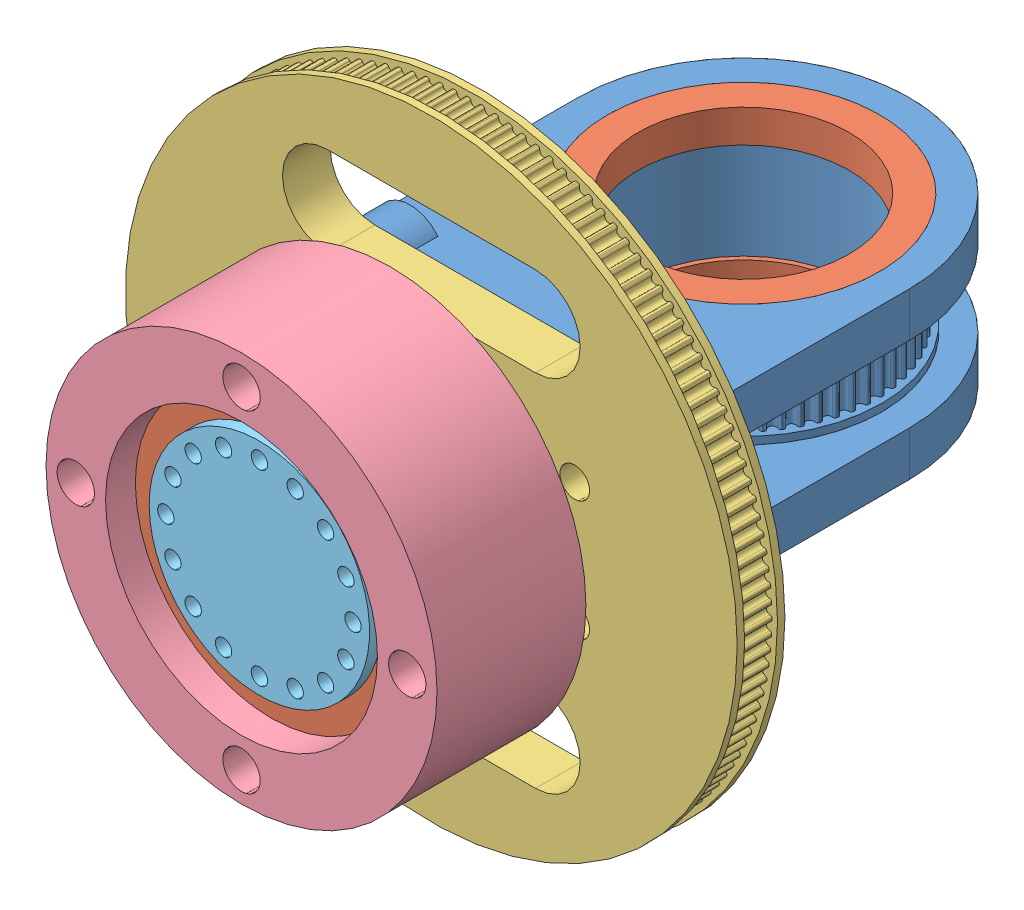
SolidWorks assembly Base, configuration Default. Lengths in mm.
Overall size (97.08 97.08 147.72).
8 component instances, 5 part files, 9 mates.
Components (placement in the parent):
- Base Joint-1: Base Joint [Default] at origin size (76.41 40.94 91.78)
- Bearing 45_58_7mm-1: Bearing 45_58_7mm [Default] at (0 14.1125 0) x (-0.796354 0 0.604831) z (0 1 0) size (58 58 7)
- Bearing 45_58_7mm-2: Bearing 45_58_7mm [Default] at (0 -14.1125 0) x (-0.796354 0 0.604831) z (0 1 0) size (58 58 7)
- Base Pulley-1: Base Pulley [Default] at (0 0 61.5165) x (0 1 0) z (1 0 0) size (97.08 44.31 97.08)
- Bearing 45_58_7mm-3: Bearing 45_58_7mm [Default] at (0 0 78.8352) x (0.359426 0.933173 0) z (0 0 -1) size (58 58 7)
- Bearing 45_58_7mm-4: Bearing 45_58_7mm [Default] at (0 0 97.2352) x (-0.999991 0.004136 0) z (0 0 -1) size (58 58 7)
- Part2^Base-1: Part2^Base [Default] at origin size (83.4 83.4 31.75) (virtual)
- Part5^Base-1: Part5^Base [Default] at origin size (47 47 2.54) (virtual)
Mates (geometry in assembly coordinates):
- Parallel1: parallel anti-aligned: plane of Bearing-1 through (0 10.6125 0) normal (0 -1 0)
- Coincident5: coincident anti-aligned: plane of Base Joint-1 through (0 10.6125 0) normal (0 1 0); plane of Bearing-1 through (0 10.6125 0) normal (0 -1 0)
- Coincident6: coincident aligned: line of Base Pulley-1 through (0 0 64.8165) axis (0 0 -1)
- Coincident7: coincident aligned: plane of Base Pulley-1 through (0 0 61.5165) normal (0 1 0)
- Coincident8: coincident anti-aligned: plane of Base Joint-1 through (-35.35 17.6125 56.429) normal (0 0 1); plane of Base Pulley-1 through (0 0 56.429) normal (0 0 -1)
- Concentric3: concentric anti-aligned: cylinder of Base Pulley-1 through (0 0 100.7352) axis (0 0 -1) radius 22.5; cylinder of Bearing 45_58_7mm-3 through (0 0 75.3352) axis (0 0 1) radius 22.5
- Coincident37: coincident anti-aligned: plane of Base Pulley-1 through (0 0 75.3352) normal (0 0 1); plane of Bearing 45_58_7mm-3 through (0 0 75.3352) normal (0 0 -1)
- Concentric4: concentric anti-aligned: cylinder of Base Pulley-1 through (0 0 100.7352) axis (0 0 -1) radius 22.5; cylinder of Bearing 45_58_7mm-4 through (0 0 93.7352) axis (0 0 1) radius 22.5
- Coincident38: coincident aligned: plane of Base Pulley-1 through (0 0 100.7352) normal (0 0 1); plane of Bearing 45_58_7mm-4 through (0 0 100.7352) normal (0 0 1)
